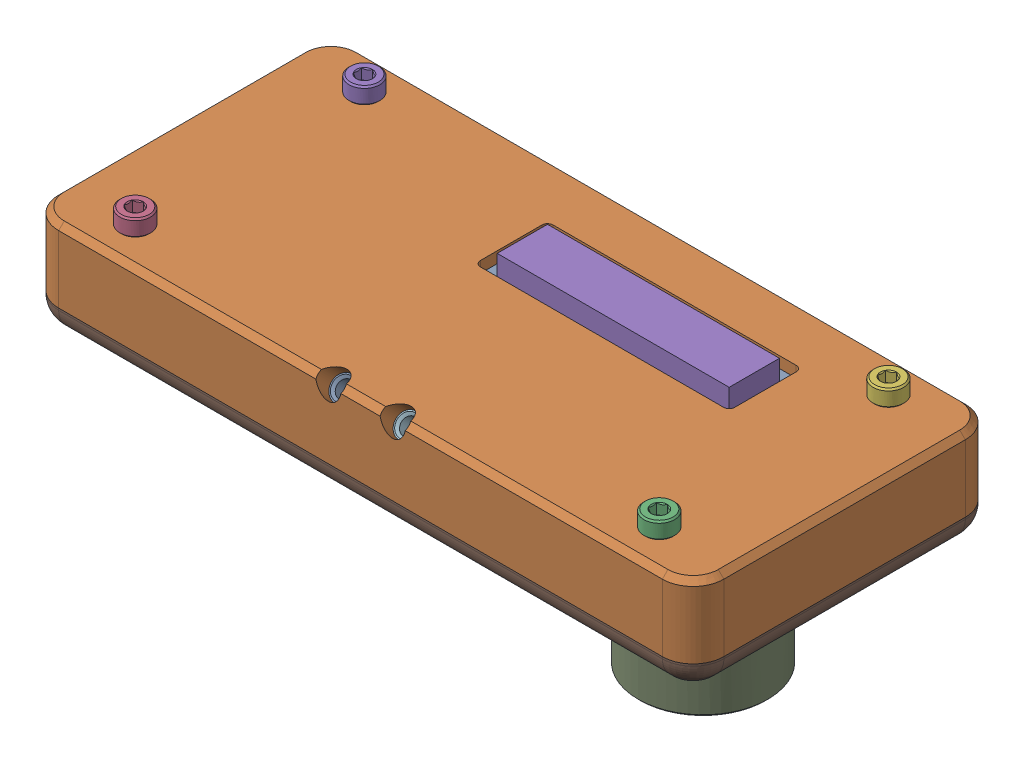
SolidWorks assembly Mini12864 Case Assembly v2 v1, configuration Default. Lengths in mm.
Overall size (119 60.88 63.47).
22 component instances, 14 part files, 0 mates.
Components (placement in the parent):
- Mini12864 Screen v1-1: Mini12864 Screen v1 [Default] at (-4.025 22.9048 -20.4173) x (1 0 0) z (0 -0.866025 -0.5) size (107.75 49.06 41.97)
  - Mini12864 Screen v1_2-1: Mini12864 Screen v1_2 [Default] at origin size (105.75 41.5 31.62)
    - Mini12864 Screen v1_4-1: Mini12864 Screen v1_4 [Default] at origin size (105.75 41.5 24.89)
    - Mini12864 Screen v1_5-1: Mini12864 Screen v1_5 [Default] at origin size (58 36.77 24.7)
    - Mini12864 Screen v1_3-1: Mini12864 Screen v1_3 [Default] at origin size (12.25 18.34 22.13)
    - Mini12864 Screen v1-1: Mini12864 Screen v1 [Default] at origin size (18.5 24.88 16.1)
    - Mini12864 Screen v1_2-1: Mini12864 Screen v1_2 [Default] at origin size (74.25 35.31 20.1)
    - Mini12864 Screen v1_6-1: Mini12864 Screen v1_6 [Default] at origin size (10 28.35 18.1)
  - Kill Button-1: Kill Button [Default] at (-0.25 0 0) size (6 9.11 11.04)
    - Kill Button-1: Kill Button [Default] at origin size (3.5 6.03 6.95)
    - Kill Button_2-1: Kill Button_2 [Default] at origin size (6 7.2 6.46)
  - Jog-1: Jog [Default] at (-74.0001 90.8894 -54.2015) x (1 0 0) z (0 0.866025 -0.5) size (30 16.2 30)
    - Jog-1: Jog [Default] at origin size (30 16 30)
    - Jog_2-1: Jog_2 [Default] at origin size (21.6 0.2 21.6)
- LCD Case Front-1: LCD Case Front [Default] at (0 21.4484 -87.5486) size (119 7 54.2)
- M3 Threaded Insert (1) (1)-1: M3 Threaded Insert (1) (1) [Default] at (57.6249 3.7155 24.4154) x (-1 0 0) z (0 -0.707107 -0.707107) size (5 5 3.85)
- M3 Threaded Insert (1) (1)-2: M3 Threaded Insert (1) (1) [Default] at (46.1249 3.7155 24.4154) x (-1 0 0) z (0 -0.707107 -0.707107) size (5 5 3.85)
- LCD Case Back-1: LCD Case Back [Default] at (51.8749 396.7029 -67.6008) size (119 13 54.2)
- M3x12 SHCS (6)-1: M3x12 SHCS (6) [Default] at (98.725 -5.6 20.5) x (1 0 0) z (0 -1 0) size (5.5 5.5 15.14)
- M3x12 SHCS (6)-2: M3x12 SHCS (6) [Default] at (4.975 -5.6 20.5) x (1 0 0) z (0 -1 0) size (5.5 5.5 15.14)
- M3x12 SHCS (6)-3: M3x12 SHCS (6) [Default] at (4.975 -5.6 -20.5) x (1 0 0) z (0 -1 0) size (5.5 5.5 15.14)
- M3x12 SHCS (6)-4: M3x12 SHCS (6) [Default] at (98.725 -5.6 -20.5) x (1 0 0) z (0 -1 0) size (5.5 5.5 15.14)
